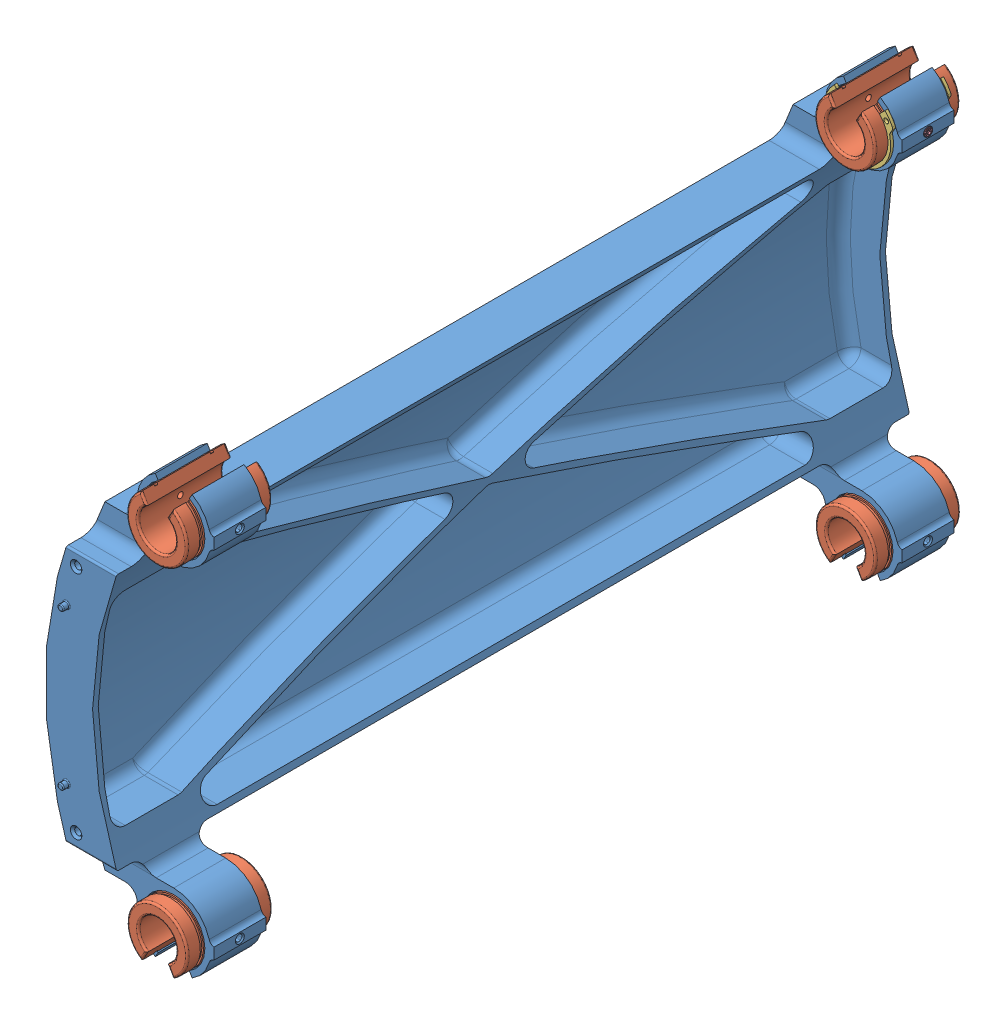
SolidWorks assembly carriage_v2_heater, configuration north. Lengths in mm.
Overall size (80.68 231.6 426.35).
8 component instances, 4 part files, 19 mates.
Components (placement in the parent):
- carriage_base-1: carriage_base [Default] at origin
- Linear_bearing_liner_FMN20_pacific_bearing-1: Linear_bearing_liner_FMN20_pacific_bearing [Default] at (-158 94 182.5)
- Linear_bearing_liner_FMN20_pacific_bearing-2: Linear_bearing_liner_FMN20_pacific_bearing [Default] at (-158 -94 182.25) x (-1 0 0) z (0 0 1)
- Linear_bearing_liner_FMN20_pacific_bearing-3: Linear_bearing_liner_FMN20_pacific_bearing [Default] at (-158 -94 -182.25) x (-1 0 0) z (0 0 1)
- Linear_bearing_liner_FMN20_pacific_bearing-4: Linear_bearing_liner_FMN20_pacific_bearing [Default] at (-158 94 -182)
- Retain_ext_modified_MC98541A139-1: Retain_ext_modified_MC98541A139 [98541A139] at (-158 94 -196.75) x (0 0 -1) z (0.714642 -0.699491 0)
- Retain_ext_modified_MC98541A139-2: Retain_ext_modified_MC98541A139 [98541A139] at (-158 94 -167.25) x (0 0 -1) z (0.712382 -0.701792 0)
- set_screw_dog_MC92505A191-1: set_screw_dog_MC92505A191 [92505A191] at (-140.025 94 -182.25) x (0 -0.792563 -0.60979) z (1 0 0)
Mates (geometry in assembly coordinates):
- Coincident1: coordinate: point of carriage_base-1; point of assembly
- Concentric1: concentric aligned: cylinder of carriage_base-1 through (-158 94 210) axis (0 0 -1) radius 16.5; cylinder of Linear_bearing_liner_FMN20_pacific_bearing-1 through (-158 94 205) axis (0 0 -1) radius 16
- Concentric2: concentric aligned: cylinder of carriage_base-1 through (-158 -94 210) axis (0 0 -1) radius 16.5; cylinder of Linear_bearing_liner_FMN20_pacific_bearing-2 through (-158 -94 204.75) axis (0 0 -1) radius 16
- Symmetric2: symmetric aligned: plane of carriage_base-1 through (-212 -68 196) normal (0 0 1); plane of carriage_base-1 through (-212 -68 168.5) normal (0 0 -1); plane of Linear_bearing_liner_FMN20_pacific_bearing-2 through (-158 -94 182.25) normal (0 0 1)
- Concentric3: concentric aligned: cylinder of carriage_base-1 through (-158 -94 210) axis (0 0 -1) radius 16.5; cylinder of Linear_bearing_liner_FMN20_pacific_bearing-3 through (-158 -94 -159.75) axis (0 0 -1) radius 16
- Symmetric3: symmetric aligned: plane of carriage_base-1 through (-212 -68 -168.5) normal (0 0 1); plane of carriage_base-1 through (-212 -68 -196) normal (0 0 -1); plane of Linear_bearing_liner_FMN20_pacific_bearing-3 through (-158 -94 -182.25) normal (0 0 1)
- Parallel1: parallel aligned: plane of Linear_bearing_liner_FMN20_pacific_bearing-1 through (-158 94 182.5) normal (1 0 0); plane of assembly through (0 0 0) normal (1 0 0)
- Parallel2: parallel anti-aligned: plane of Linear_bearing_liner_FMN20_pacific_bearing-2; plane of assembly through (0 0 0) normal (1 0 0)
- Parallel3: parallel anti-aligned: plane of Linear_bearing_liner_FMN20_pacific_bearing-3; plane of assembly through (0 0 0) normal (1 0 0)
- Coincident17: coincident aligned: plane of carriage_base-1 through (-212 68 168.5) normal (0 0 -1); plane of Linear_bearing_liner_FMN20_pacific_bearing-1 through (-158 94 168.5) normal (0 0 -1)
- Parallel4: parallel aligned: plane of Linear_bearing_liner_FMN20_pacific_bearing-4 through (-158 94 -182) normal (1 0 0); plane of assembly through (0 0 0) normal (1 0 0)
- Concentric5: concentric aligned: cylinder of carriage_base-1 through (-158 94 210) axis (0 0 -1) radius 16.5; cylinder of Linear_bearing_liner_FMN20_pacific_bearing-4 through (-158 94 -159.5) axis (0 0 -1) radius 16
- Coincident18: coincident aligned: plane of carriage_base-1 through (-212 68 -196) normal (0 0 -1); plane of Linear_bearing_liner_FMN20_pacific_bearing-4 through (-158 94 -196) normal (0 0 -1)
- Concentric7: concentric anti-aligned: cylinder of Linear_bearing_liner_FMN20_pacific_bearing-4 through (-158 94 -159.5) axis (0 0 -1) radius 10; cylinder of Retain_ext_modified_MC98541A139-1 through (-158 94 -197.5) axis (0 0 1) radius 14.8
- Coincident19: coincident anti-aligned: plane of carriage_base-1 through (-212 68 -196) normal (0 0 -1); plane of Retain_ext_modified_MC98541A139-1 through (-158 94 -196) normal (0 0 1)
- Concentric8: concentric anti-aligned: cylinder of Linear_bearing_liner_FMN20_pacific_bearing-4 through (-158 94 -159.5) axis (0 0 -1) radius 10; cylinder of Retain_ext_modified_MC98541A139-2 through (-158 94 -168) axis (0 0 1) radius 14.8
- Coincident20: coincident anti-aligned: plane of Linear_bearing_liner_FMN20_pacific_bearing-4 through (-158 94 -168) normal (0 0 1); plane of Retain_ext_modified_MC98541A139-2 through (-158 94 -168) normal (0 0 -1)
- Concentric9: concentric anti-aligned: cylinder of set_screw_dog_MC92505A191-1 through (-144.5023 94 -182.25) axis (-1 0 0) radius 1.3843; cylinder of carriage_base-1 through (-136.7322 94 -182.25) axis (1 0 0) radius 1.7272
- Distance1: distance = 0.6759 mm aligned: plane of carriage_base-1 through (-136.7322 91 210) normal (1 0 0); plane of set_screw_dog_MC92505A191-1 through (-136.0563 94 -182.25) normal (1 0 0)
